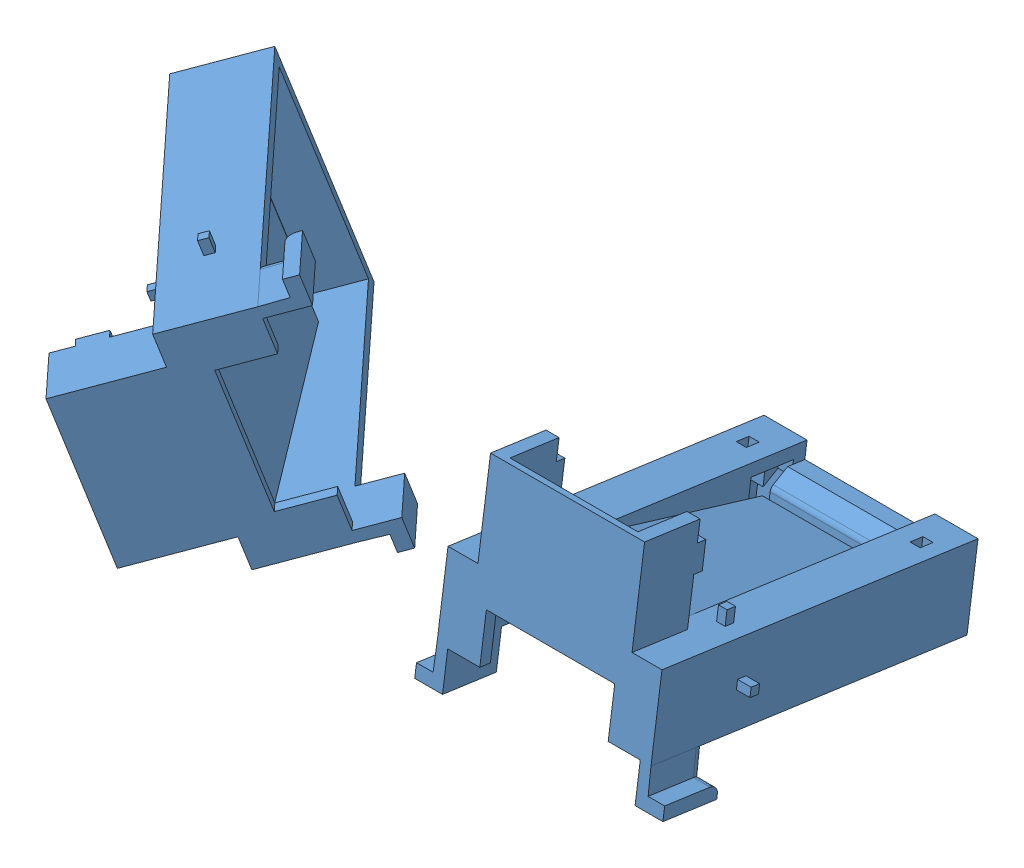
SolidWorks assembly Assem1, configuration Default. Lengths in mm.
Overall size (180.94 70.61 104.91).
2 component instances, 1 part files, 9 mates.
Components (placement in the parent):
- preferenceV2_dispenser_trough_separateMount-1: preferenceV2_dispenser_trough_separateMount [78] at (0 8.6341 -37.4617) x (1 0 0) z (0 0.139446 0.99023) size (58 48.22 77.76)
- preferenceV2_dispenser_trough_separateMount-2: preferenceV2_dispenser_trough_separateMount [78] at (-124.1373 26.9438 -19.6664) x (-0.240578 0.94466 0.223024) z (0.679846 0 0.733355) size (58 48.22 77.76)
Mates (geometry in assembly coordinates):
- Coincident1: coincident: plane of preferenceV2_dispenser_trough_separateMount-1 through (0 0 29.6985) normal (0 -0.99023 0.139446); line of preferenceV2_dispenser_trough_separateMount-2 through (-71.4683 0.3093 37.8682) axis (-0.679846 0 -0.733355)
- Coincident2: coincident: plane of preferenceV2_dispenser_trough_separateMount-1 through (0 0 29.6985) normal (0 -0.99023 0.139446); line of preferenceV2_dispenser_trough_separateMount-2 through (-87.7699 0 52.9803) axis (-0.679846 0 -0.733355)
- Coincident4: coincident aligned: plane of preferenceV2_dispenser_trough_separateMount-1 through (0 8.6341 -37.4617) normal (1 0 0)
- Coincident5: coincident: line of preferenceV2_dispenser_trough_separateMount-1 through (29 0 29.6985) axis (-1 0 0)
- Coincident7: coincident: line of preferenceV2_dispenser_trough_separateMount-1 through (29 0 29.6985) axis (-1 0 0)
- Coincident8: coincident: line of preferenceV2_dispenser_trough_separateMount-1 through (25 0 -32.7988) axis (-1 0 0)
- Coincident9: coincident: point of preferenceV2_dispenser_trough_separateMount-1
- Coincident10: coincident: line of preferenceV2_dispenser_trough_separateMount-2 through (-77.9408 0 17.9601) axis (-0.679846 0 -0.733355)
- Coincident11: coincident: line of preferenceV2_dispenser_trough_separateMount-2 through (-87.7699 0 52.9803) axis (-0.679846 0 -0.733355)
